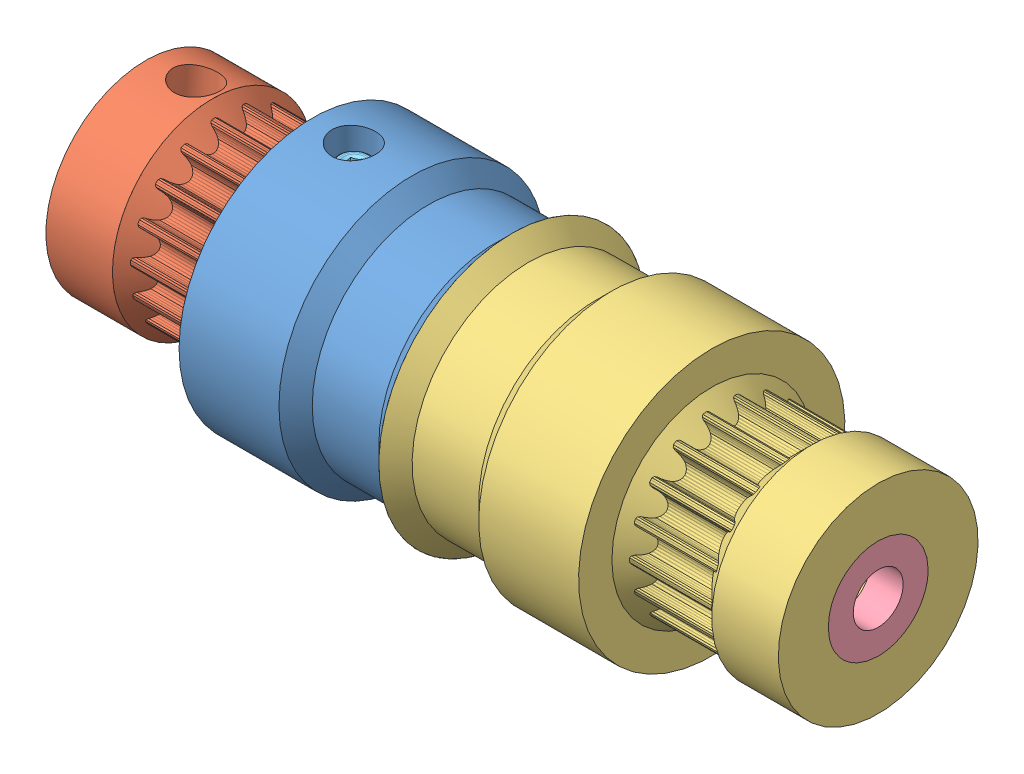
SolidWorks assembly Bobbin_assem_v2, configuration Default. Lengths in mm.
Overall size (44 16 16).
9 component instances, 5 part files, 13 mates.
Components (placement in the parent):
- GT2_Bobbin_v2-2: GT2_Bobbin_v2 [Default] at (1.9835 9.7041 8.928) size (12 16 16)
- GT2_Spur_v2_18tooth-1: GT2_Spur_v2_18tooth [Default] at (16.9835 9.7041 8.928) x (0 0.088519 0.996074) z (-1 0 0) size (12 12 15)
- GT2_Bobbin_Idler_v2-2: GT2_Bobbin_Idler_v2 [Default] at (10.9835 9.7041 8.928) x (0 0 -1) z (1 0 0) size (16 16 22)
- bearing_3x6x2-1: bearing_3x6x2 [Default] at (11.9835 9.7041 8.928) x (1 0 0) z (0 0.026748 0.999642) size (2 6 6)
- bearing_3x6x2-2: bearing_3x6x2 [Default] at (4.9835 9.7041 8.928) x (1 0 0) z (0 0.473959 0.880547) size (2 6 6)
- bearing_3x6x2-3: bearing_3x6x2 [Default] at (15.9835 9.7041 8.928) x (-1 0 0) z (0 0 -1) size (2 6 6)
- bearing_3x6x2-4: bearing_3x6x2 [Default] at (35.9835 9.7041 8.928) x (-1 0 0) z (0 -0.954997 -0.296616) size (2 6 6)
- setScrew_M2x2_5_92015A207-1: setScrew_M2x2_5_92015A207 [92015A207] at (4.4835 15.5687 8.928) x (1 0 0) z (0 1 0) size (2.31 2.07 2.9)
- setScrew_M2x2_5_92015A207-3: setScrew_M2x2_5_92015A207 [92015A207] at (4.4835 3.8733 8.928) x (1 0 0) z (0 -1 0) size (2.31 2.07 2.9)
Mates (geometry in assembly coordinates):
- Coincident2: coincident anti-aligned: plane of GT2_Bobbin_v2-2 through (6.9835 14.2041 8.928) normal (-1 0 0); plane of bearing_3x6x2-2 through (6.9835 12.3457 7.5061) normal (1 0 0)
- Concentric3: concentric aligned: cylinder of GT2_Bobbin_v2-2 through (1.9835 9.7041 8.928) axis (-1 0 0) radius 3; cylinder of bearing_3x6x2-1 through (11.9835 9.7041 8.928) axis (-1 0 0) radius 3
- Coincident3: coincident aligned: plane of GT2_Bobbin_v2-2 through (13.9835 17.7041 8.928) normal (1 0 0); plane of bearing_3x6x2-1 through (13.9835 12.703 8.8478) normal (1 0 0)
- Concentric5: concentric anti-aligned: cylinder of GT2_Bobbin_Idler_v2-2 through (10.9835 9.7041 8.928) axis (-1 0 0) radius 3; cylinder of bearing_3x6x2-3 through (15.9835 9.7041 8.928) axis (1 0 0) radius 3
- Coincident5: coincident aligned: plane of GT2_Bobbin_Idler_v2-2 through (13.9835 12.7041 8.928) normal (-1 0 0); plane of bearing_3x6x2-3 through (13.9835 12.7041 8.928) normal (-1 0 0)
- Concentric6: concentric anti-aligned: cylinder of bearing_3x6x2-1 through (11.9835 9.7041 8.928) axis (-1 0 0) radius 1.5; cylinder of bearing_3x6x2-3 through (15.9835 9.7041 8.928) axis (1 0 0) radius 1.5
- Coincident6: coincident anti-aligned: plane of GT2_Bobbin_v2-2 through (13.9835 17.7041 8.928) normal (1 0 0); plane of GT2_Bobbin_Idler_v2-2 through (13.9835 12.7041 8.928) normal (-1 0 0)
- Concentric7: concentric aligned: cylinder of GT2_Bobbin_v2-2 through (4.4835 1.7041 8.928) axis (0 1 0) radius 1.3; line of setScrew_M2x2_5_92015A207-1 through (4.4835 14.4833 8.928) axis (0 1 0)
- Tangent2: tangent: cylinder of GT2_Spur_v2_18tooth-1 through (16.9835 9.7041 8.928) axis (1 0 0) radius 4.45; circle of setScrew_M2x2_5_92015A207-1
- Concentric10: concentric anti-aligned: cylinder of GT2_Spur_v2_18tooth-1 through (16.9835 9.7041 8.928) axis (1 0 0) radius 3; cylinder of bearing_3x6x2-2 through (4.9835 9.7041 8.928) axis (-1 0 0) radius 3
- Concentric11: concentric anti-aligned: cylinder of GT2_Bobbin_v2-2 through (1.9835 9.7041 8.928) axis (-1 0 0) radius 4.5; cylinder of GT2_Spur_v2_18tooth-1 through (16.9835 9.7041 8.928) axis (1 0 0) radius 4.45
- Concentric12: concentric aligned: cylinder of GT2_Bobbin_Idler_v2-2 through (33.9835 9.7041 8.928) axis (1 0 0) radius 3; cylinder of bearing_3x6x2-4 through (35.9835 9.7041 8.928) axis (1 0 0) radius 3
- Coincident7: coincident anti-aligned: plane of GT2_Bobbin_Idler_v2-2 through (33.9835 9.7041 8.928) normal (1 0 0); plane of bearing_3x6x2-4 through (33.9835 10.5939 6.063) normal (-1 0 0)
